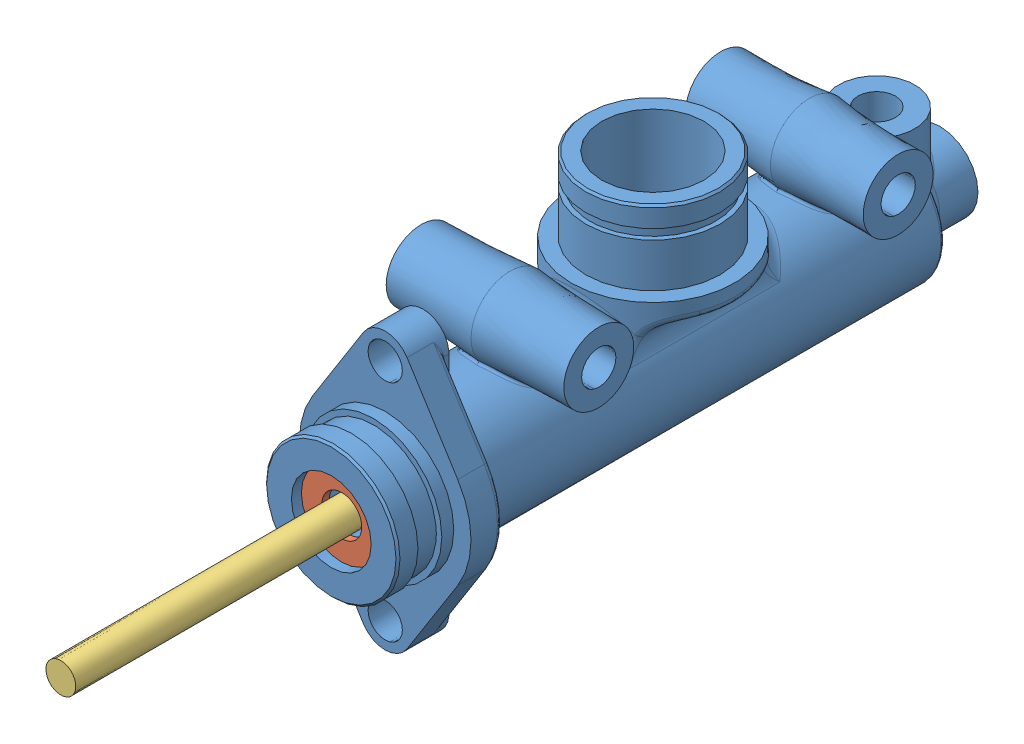
SolidWorks assembly mastercylinder asm, configuration Default. Lengths in mm.
Overall size (45.21 75.99 223.71).
3 component instances, 3 part files, 4 mates.
Components (placement in the parent):
- mastercylinder-1: mastercylinder [Default] at origin size (45.21 75.99 154.88)
- mastercylinder retaining washer-1: mastercylinder retaining washer [Default] at (0 0 17.145) size (20.83 20.83 1.91)
- mastercylinder pushrod-1: mastercylinder pushrod [Default] at (0 0 90.551) x (-0.12806 0.991766 0) z (0 0 1) size (10.67 10.67 107.24)
Mates (geometry in assembly coordinates):
- Coincident1: coincident anti-aligned: plane of mastercylinder-1 through (0 0 17.145) normal (0 0 1); plane of mastercylinder retaining washer-1 through (0 0 17.145) normal (0 0 -1)
- Concentric1: concentric anti-aligned: cylinder of mastercylinder-1 through (0 0 17.145) axis (0 0 1) radius 10.414; cylinder of mastercylinder retaining washer-1 through (0 0 19.05) axis (0 0 -1) radius 10.414
- Concentric2: concentric aligned: cylinder of mastercylinder-1 through (0 0 -105.283) axis (0 0 1) radius 10.16; cylinder of mastercylinder pushrod-1 through (0 0 90.551) axis (0 0 1) radius 3.81
- Distance1: distance = 82.55 mm aligned: plane of mastercylinder pushrod-1 through (0 0 90.551) normal (0 0 1); plane of mastercylinder-1 through (0 28.575 8.001) normal (0 0 1)
